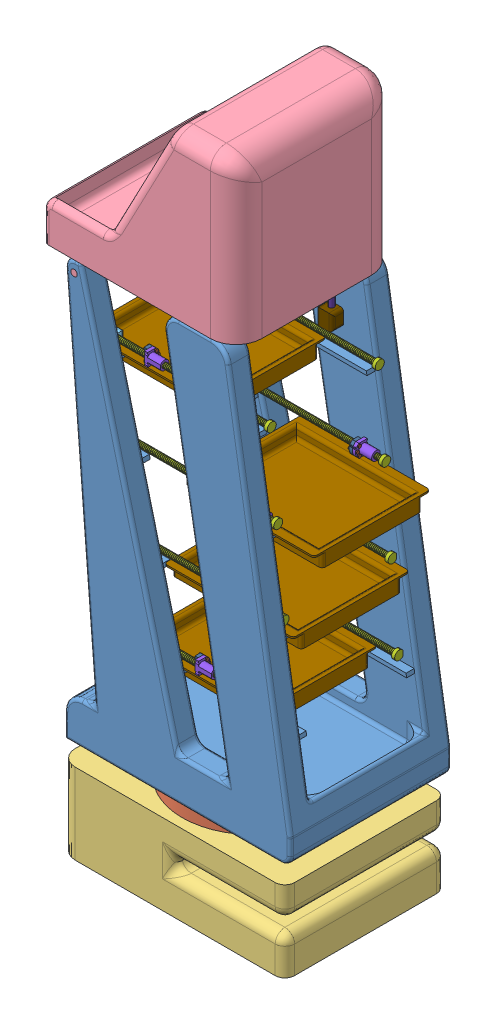
SolidWorks assembly Złożenie1, configuration Domyślna. Lengths in mm.
Overall size (771.86 2135.15 517.31).
75 component instances, 18 part files, 137 mates.
Components (placement in the parent):
- robot_K_1-1: robot_K_1 [Domyślna] at (-167.6884 -51.2285 36.3099) size (700 1300 500)
- robot_K_2-2: robot_K_2 [Domyślna] at (167.3116 -161.2285 286.3099) size (440 200 440)
- robot_K_3-4: robot_K_3 [Domyślna] at (-62.1274 -411.2285 345.4972) x (0 0 -1) z (1 0 0) size (500 250 700)
- robot_K_4-1: robot_K_4 [Domyślna] at (-23.7623 1556.5601 36.3099) size (600 550 517.31)
- motorL-2: motorL [Domyślna] at (-78.6565 231.7434 476.7772) x (0 0 -1) z (0 -1 0) size (37.5 50 47)
- motorL-3: motorL [Domyślna] at (-98.8446 481.7434 476.7772) x (0 0 -1) z (0 -1 0) size (37.5 50 47)
- motorL-4: motorL [Domyślna] at (-118.6565 731.7434 476.7772) x (0 0 -1) z (0 -1 0) size (37.5 50 47)
- motorL-5: motorL [Domyślna] at (-138.6565 981.7434 476.7772) x (0 0 -1) z (0 -1 0) size (37.5 50 47)
- motorR-1: motorR [Domyślna] at (-138.6565 981.7434 116.7772) x (0 0 -1) z (0 -1 0) size (37.5 50 47)
- motorR-2: motorR [Domyślna] at (-118.6565 731.7434 116.7772) x (0 0 -1) z (0 -1 0) size (37.5 50 47)
- motorR-3: motorR [Domyślna] at (-78.6565 231.7434 116.7772) x (0 0 -1) z (0 -1 0) size (37.5 50 47)
- motorR-4: motorR [Domyślna] at (-98.8446 481.7434 116.7772) x (0 0 -1) z (0 -1 0) size (37.5 50 47)
- śruba-1: śruba [Domyślna] at (382.3435 973.7715 118.8099) x (0 0.000202 -1) z (-1 0 0) size (28 28 531.75)
- śruba-2: śruba [Domyślna] at (382.3435 973.7715 453.8099) x (0 0.000188 -1) z (-1 0 0) size (28 28 531.75)
- nakretka-14: nakretka [Default] at (9.7434 973.7715 118.8099) x (1 0 0) z (0 -1 0) size (50 36.5 40)
- nakretka-16: nakretka [Default] at (9.7434 973.7715 453.8099) x (1 0 0) z (0 1 0) size (50 36.5 40)
- tacka-8: tacka [Domyślna] at (-12.1899 908.7715 289.7766) x (0 0 -1) z (1 0 0) size (360 45 400)
- mocowanie_tacka-13: mocowanie_tacka [Default] at (-0.2566 973.7715 118.8099) x (1 0 0) z (0 -1 0) size (10 27.5 40)
- mocowanie_tacka-14: mocowanie_tacka [Default] at (-0.2566 973.7715 453.8099) x (1 0 0) z (0 1 0) size (10 27.5 40)
- sruba_mocowanie-1: sruba_mocowanie [Domyślna] at (-0.2566 960.3365 440.3749) x (0 -0.000382 -1) z (1 0 0) size (10 10 26)
- sruba_mocowanie-3: sruba_mocowanie [Domyślna] at (-0.2566 973.7715 137.8099) x (0 0.000323 -1) z (1 0 0) size (10 10 26)
- sruba_mocowanie-4: sruba_mocowanie [Domyślna] at (-0.2566 960.3365 132.2449) x (0 0.000323 -1) z (1 0 0) size (10 10 26)
- sruba_mocowanie-5: sruba_mocowanie [Domyślna] at (-0.2566 987.2065 132.2449) x (0 0.000323 -1) z (1 0 0) size (10 10 26)
- sruba_mocowanie-6: sruba_mocowanie [Domyślna] at (-0.2566 987.2065 440.3749) x (0 -0.000382 -1) z (1 0 0) size (10 10 26)
- sruba_mocowanie-7: sruba_mocowanie [Domyślna] at (-0.2566 973.7715 434.8099) x (0 -0.000382 -1) z (1 0 0) size (10 10 26)
- sruba_mocowanie-8: sruba_mocowanie [Domyślna] at (321.002 723.7715 434.8099) x (0 -0.000382 -1) z (1 0 0) size (10 10 26)
- sruba_mocowanie-9: sruba_mocowanie [Domyślna] at (321.002 737.2065 440.3749) x (0 -0.000382 -1) z (1 0 0) size (10 10 26)
- sruba_mocowanie-10: sruba_mocowanie [Domyślna] at (321.002 737.2065 132.2449) x (0 0.000323 -1) z (1 0 0) size (10 10 26)
- sruba_mocowanie-11: sruba_mocowanie [Domyślna] at (321.002 710.3365 132.2449) x (0 0.000323 -1) z (1 0 0) size (10 10 26)
- sruba_mocowanie-12: sruba_mocowanie [Domyślna] at (321.002 723.7715 137.8099) x (0 0.000323 -1) z (1 0 0) size (10 10 26)
- sruba_mocowanie-13: sruba_mocowanie [Domyślna] at (321.002 710.3365 440.3749) x (0 -0.000382 -1) z (1 0 0) size (10 10 26)
- mocowanie_tacka-15: mocowanie_tacka [Default] at (321.002 723.7715 453.8099) x (1 0 0) z (0 1 0) size (10 27.5 40)
- mocowanie_tacka-16: mocowanie_tacka [Default] at (321.002 723.7715 118.8099) x (1 0 0) z (0 -1 0) size (10 27.5 40)
- tacka-9: tacka [Domyślna] at (309.0687 658.7715 289.7766) x (0 0 -1) z (1 0 0) size (360 45 400)
- nakretka-17: nakretka [Default] at (331.002 723.7715 453.8099) x (1 0 0) z (0 1 0) size (50 36.5 40)
- nakretka-18: nakretka [Default] at (331.002 723.7715 118.8099) x (1 0 0) z (0 -1 0) size (50 36.5 40)
- śruba-3: śruba [Domyślna] at (402.3435 723.7715 453.8099) x (0 0.000188 -1) z (-1 0 0) size (28 28 531.75)
- śruba-4: śruba [Domyślna] at (402.3435 723.7715 118.8099) x (0 0.000202 -1) z (-1 0 0) size (28 28 531.75)
- sruba_mocowanie-14: sruba_mocowanie [Domyślna] at (256.3597 473.7715 434.8099) x (0 -0.000382 -1) z (1 0 0) size (10 10 26)
- sruba_mocowanie-15: sruba_mocowanie [Domyślna] at (256.3597 487.2065 440.3749) x (0 -0.000382 -1) z (1 0 0) size (10 10 26)
- sruba_mocowanie-16: sruba_mocowanie [Domyślna] at (256.3597 487.2065 132.2449) x (0 0.000323 -1) z (1 0 0) size (10 10 26)
- sruba_mocowanie-17: sruba_mocowanie [Domyślna] at (256.3597 460.3365 132.2449) x (0 0.000323 -1) z (1 0 0) size (10 10 26)
- sruba_mocowanie-18: sruba_mocowanie [Domyślna] at (256.3597 473.7715 137.8099) x (0 0.000323 -1) z (1 0 0) size (10 10 26)
- sruba_mocowanie-19: sruba_mocowanie [Domyślna] at (256.3597 460.3365 440.3749) x (0 -0.000382 -1) z (1 0 0) size (10 10 26)
- mocowanie_tacka-17: mocowanie_tacka [Default] at (256.3597 473.7715 453.8099) x (1 0 0) z (0 1 0) size (10 27.5 40)
- mocowanie_tacka-18: mocowanie_tacka [Default] at (256.3597 473.7715 118.8099) x (1 0 0) z (0 -1 0) size (10 27.5 40)
- tacka-10: tacka [Domyślna] at (244.4263 408.7715 289.7766) x (0 0 -1) z (1 0 0) size (360 45 400)
- nakretka-19: nakretka [Default] at (266.3597 473.7715 453.8099) x (1 0 0) z (0 1 0) size (50 36.5 40)
- nakretka-20: nakretka [Default] at (266.3597 473.7715 118.8099) x (1 0 0) z (0 -1 0) size (50 36.5 40)
- śruba-5: śruba [Domyślna] at (422.1554 473.7715 453.8099) x (0 0.000188 -1) z (-1 0 0) size (28 28 531.75)
- śruba-6: śruba [Domyślna] at (422.1554 473.7715 118.8099) x (0 0.000202 -1) z (-1 0 0) size (28 28 531.75)
- sruba_mocowanie-20: sruba_mocowanie [Domyślna] at (157.5731 223.7715 434.8099) x (0 -0.000382 -1) z (1 0 0) size (10 10 26)
- sruba_mocowanie-21: sruba_mocowanie [Domyślna] at (157.5731 237.2065 440.3749) x (0 -0.000382 -1) z (1 0 0) size (10 10 26)
- sruba_mocowanie-22: sruba_mocowanie [Domyślna] at (157.5731 237.2065 132.2449) x (0 0.000323 -1) z (1 0 0) size (10 10 26)
- sruba_mocowanie-23: sruba_mocowanie [Domyślna] at (157.5731 210.3365 132.2449) x (0 0.000323 -1) z (1 0 0) size (10 10 26)
- sruba_mocowanie-24: sruba_mocowanie [Domyślna] at (157.5731 223.7715 137.8099) x (0 0.000323 -1) z (1 0 0) size (10 10 26)
- sruba_mocowanie-25: sruba_mocowanie [Domyślna] at (157.5731 210.3365 440.3749) x (0 -0.000382 -1) z (1 0 0) size (10 10 26)
- mocowanie_tacka-19: mocowanie_tacka [Default] at (157.5731 223.7715 453.8099) x (1 0 0) z (0 1 0) size (10 27.5 40)
- mocowanie_tacka-20: mocowanie_tacka [Default] at (157.5731 223.7715 118.8099) x (1 0 0) z (0 -1 0) size (10 27.5 40)
- tacka-11: tacka [Domyślna] at (145.6398 158.7715 289.7766) x (0 0 -1) z (1 0 0) size (360 45 400)
- nakretka-21: nakretka [Default] at (167.5731 223.7715 453.8099) x (1 0 0) z (0 1 0) size (50 36.5 40)
- nakretka-22: nakretka [Default] at (167.5731 223.7715 118.8099) x (1 0 0) z (0 -1 0) size (50 36.5 40)
- śruba-7: śruba [Domyślna] at (442.3435 223.7715 453.8099) x (0 0.000188 -1) z (-1 0 0) size (28 28 531.75)
- śruba-8: śruba [Domyślna] at (442.3435 223.7715 118.8099) x (0 0.000202 -1) z (-1 0 0) size (28 28 531.75)
- kolo_D-1: kolo_D [Domyślna] at (320.5228 -376.2285 486.3099) x (0.002489 -0.999997 0) z (0.999997 0.002489 0) size (120 70 120)
- kolo_D-2: kolo_D [Domyślna] at (320.5228 -376.2285 156.3099) x (0.002489 -0.999997 0) z (0.999997 0.002489 0) size (120 70 120)
- do_kola_m-1: do_kola_m [Domyślna] at (-42.0368 -394.1457 263.6106) x (0.819465 0 0.573129) z (-0.573129 0 0.819465) size (40 70 40)
- kolo_M-1: kolo_M [Domyślna] at (-35.8803 -396.2285 274.0179) x (0.819465 0 0.573129) z (-0.573129 0 0.819465) size (50 50 30)
- do_kola_Mm-1: do_kola_Mm [Domyślna] at (-33.0147 -396.2285 269.9206) x (0.819465 0 0.573129) z (0 -1 0) size (16 50 16)
- mocowanie_mechanizmT-1: mocowanie_mechanizmT [Default] at (242.9316 1148.7715 118.8099) x (0 1 0) z (1 0 0) size (50 66.5 40)
- mocowanie_mechanizmT-2: mocowanie_mechanizmT [Default] at (242.9316 1148.7715 453.8099) x (0 1 0) z (-1 0 0) size (50 66.5 40)
- śruba_T-1: śruba_T [Domyślna] at (242.9316 1188.7715 118.8099) x (0.974399 0 -0.224824) z (0 -1 0) size (28 28 190)
- śruba_T-2: śruba_T [Domyślna] at (242.9316 1188.7715 453.8099) x (-0.680666 0 0.732594) z (0 -1 0) size (28 28 190)
- motorT-1: motorT [Domyślna] at (219.9643 1006.7715 432.338) size (50 50 36.09)
- motorT-2: motorT [Domyślna] at (265.899 1006.7715 140.2818) x (-1 0 0) z (0 0 -1) size (50 50 36.09)
Mates (geometry in assembly coordinates):
- Wspólnie2: coincident anti-aligned: circle of robot_K_1-1; circle of robot_K_2-2
- Wspólnie4: coincident anti-aligned: circle of robot_K_2-2; circle of robot_K_3-4
- Wspólnie5: coincident anti-aligned: circle of robot_K_1-1; circle of robot_K_4-1
- Równolegle1: parallel anti-aligned: plane of robot_K_1-1 through (-63.9094 948.7715 441.3099) normal (0 1 0); plane of motorL-5 through (-137.6565 948.7715 466.3099) normal (0 -1 0)
- Wspólnie22: coincident aligned: line of robot_K_1-1 through (-137.6565 948.7715 441.3099) axis (0 0 1); line of motorL-5 through (-137.6565 948.7715 441.3099) axis (0 0 1)
- Wspólnie26: coincident aligned: line of robot_K_1-1 through (-117.6565 698.7715 441.3099) axis (0 0 1); line of motorL-4 through (-117.6565 698.7715 441.3099) axis (0 0 1)
- Wspólnie28: coincident: point of robot_K_1-1; line of motorL-3 through (-97.8446 448.7715 441.3099) axis (0 0 1)
- Wspólnie30: coincident: unknown of robot_K_1-1; line of motorL-2 through (-77.6565 198.7715 441.3099) axis (0 0 1)
- Wspólnie31: coincident anti-aligned: plane of robot_K_1-1 through (-167.6884 38.7715 106.3099) normal (0 0 1); plane of motorR-1 through (-138.6565 981.7434 106.3099) normal (0 0 -1)
- Wspólnie32: coincident aligned: line of robot_K_1-1 through (-137.6565 948.7715 131.3099) axis (0 0 -1); line of motorR-1 through (-137.6565 948.7715 131.3099) axis (0 0 -1)
- Wspólnie33: coincident anti-aligned: plane of robot_K_1-1 through (-167.6884 38.7715 106.3099) normal (0 0 1); plane of motorR-2 through (-118.6565 731.7434 106.3099) normal (0 0 -1)
- Wspólnie34: coincident: unknown of robot_K_1-1; line of motorR-2 through (-117.6565 698.7715 131.3099) axis (0 0 -1)
- Wspólnie36: coincident anti-aligned: plane of robot_K_1-1 through (-167.6884 38.7715 106.3099) normal (0 0 1); plane of motorR-4 through (-98.8446 481.7434 106.3099) normal (0 0 -1)
- Wspólnie37: coincident aligned: line of robot_K_1-1 through (-97.8446 448.7715 131.3099) axis (0 0 -1); line of motorR-4 through (-97.8446 448.7715 131.3099) axis (0 0 -1)
- Wspólnie38: coincident anti-aligned: plane of robot_K_1-1 through (-167.6884 38.7715 106.3099) normal (0 0 1); plane of motorR-3 through (-78.6565 231.7434 106.3099) normal (0 0 -1)
- Wspólnie39: coincident: unknown of robot_K_1-1; line of motorR-3 through (-77.6565 198.7715 131.3099) axis (0 0 -1)
- Koncentryczne3: concentric anti-aligned: circle of motorL-5; circle of śruba-2
- Wspólnie49: coincident aligned: circle of motorR-1; circle of śruba-1
- Wspólnie110: coincident anti-aligned: plane of nakretka-14 through (9.7434 973.7715 134.8099) normal (-1 0 0); plane of mocowanie_tacka-13 through (9.7434 973.7715 137.8099) normal (1 0 0)
- Wspólnie111: coincident aligned: circle of nakretka-14; circle of mocowanie_tacka-13
- Wspólnie112: coincident anti-aligned: plane of nakretka-14 through (9.7434 953.7715 144.8099) normal (0 -1 0); plane of tacka-8 through (-12.1899 953.7715 289.7766) normal (0 1 0)
- Wspólnie113: coincident anti-aligned: plane of nakretka-16 through (9.7434 973.7715 437.8099) normal (-1 0 0); plane of mocowanie_tacka-14 through (9.7434 973.7715 434.8099) normal (1 0 0)
- Wspólnie114: coincident aligned: circle of nakretka-16; circle of mocowanie_tacka-14
- Wspólnie115: coincident anti-aligned: plane of nakretka-16 through (9.7434 953.7715 477.8099) normal (0 -1 0); plane of tacka-8 through (-12.1899 953.7715 289.7766) normal (0 1 0)
- Wspólnie117: coincident anti-aligned: circle of nakretka-16; circle of sruba_mocowanie-6
- Wspólnie120: coincident anti-aligned: circle of nakretka-16; circle of sruba_mocowanie-7
- Wspólnie121: coincident anti-aligned: circle of nakretka-16; circle of sruba_mocowanie-1
- Wspólnie122: coincident anti-aligned: circle of nakretka-14; circle of sruba_mocowanie-5
- Wspólnie123: coincident anti-aligned: circle of nakretka-14; circle of sruba_mocowanie-3
- Wspólnie124: coincident anti-aligned: circle of nakretka-14; circle of sruba_mocowanie-4
- Koncentryczne19: concentric anti-aligned: cylinder of śruba-1 through (-137.6565 973.7715 118.8099) axis (1 0 0) radius 8; cylinder of nakretka-14 through (34.7434 973.7715 118.8099) axis (-1 0 0) radius 8
- Koncentryczne20: concentric anti-aligned: cylinder of śruba-2 through (-137.6565 973.7715 453.8099) axis (1 0 0) radius 8; cylinder of nakretka-16 through (34.7434 973.7715 453.8099) axis (-1 0 0) radius 8
- Wspólnie136: coincident aligned: line of nakretka-14 through (19.7434 953.7715 106.3099) axis (-1 0 0); line of tacka-8 through (204.7434 953.7715 106.3099) axis (-1 0 0)
- Wspólnie137: coincident: unknown of nakretka-14; unknown of tacka-8
- Wspólnie138: coincident: line of nakretka-16 through (19.7434 953.7715 466.3099) axis (-1 0 0); plane of tacka-8 through (-185.2566 953.7715 466.3099) normal (0 0 1)
- Wspólnie139: coincident: unknown of nakretka-16; unknown of tacka-8
- Wspólnie141: coincident anti-aligned: circle of motorL-5; circle of śruba-2
- Wspólnie142: coincident: unknown of tacka-9; unknown of nakretka-18
- Wspólnie143: coincident aligned: line of tacka-9 through (526.002 703.7715 106.3099) axis (-1 0 0); line of nakretka-18 through (341.002 703.7715 106.3099) axis (-1 0 0)
- Wspólnie144: coincident anti-aligned: plane of mocowanie_tacka-15 through (331.002 723.7715 434.8099) normal (1 0 0); plane of nakretka-17 through (331.002 723.7715 437.8099) normal (-1 0 0)
- Wspólnie145: coincident aligned: circle of mocowanie_tacka-16; circle of nakretka-18
- Wspólnie146: coincident anti-aligned: plane of tacka-9 through (309.0687 703.7715 289.7766) normal (0 1 0); plane of nakretka-18 through (331.002 703.7715 144.8099) normal (0 -1 0)
- Wspólnie147: coincident anti-aligned: circle of sruba_mocowanie-9; circle of nakretka-17
- Wspólnie148: coincident anti-aligned: circle of sruba_mocowanie-8; circle of nakretka-17
- Wspólnie149: coincident: plane of tacka-9 through (136.002 703.7715 466.3099) normal (0 0 1); line of nakretka-17 through (341.002 703.7715 466.3099) axis (-1 0 0)
- Wspólnie150: coincident: unknown of tacka-9; unknown of nakretka-17
- Wspólnie151: coincident anti-aligned: plane of mocowanie_tacka-16 through (331.002 723.7715 137.8099) normal (1 0 0); plane of nakretka-18 through (331.002 723.7715 134.8099) normal (-1 0 0)
- Wspólnie152: coincident anti-aligned: circle of sruba_mocowanie-11; circle of nakretka-18
- Wspólnie153: coincident anti-aligned: circle of sruba_mocowanie-12; circle of nakretka-18
- Koncentryczne21: concentric anti-aligned: cylinder of nakretka-18 through (356.002 723.7715 118.8099) axis (-1 0 0) radius 8; cylinder of śruba-4 through (-117.6565 723.7715 118.8099) axis (1 0 0) radius 8
- Koncentryczne22: concentric anti-aligned: cylinder of nakretka-17 through (356.002 723.7715 453.8099) axis (-1 0 0) radius 8; cylinder of śruba-3 through (-117.6565 723.7715 453.8099) axis (1 0 0) radius 8
- Wspólnie154: coincident anti-aligned: circle of sruba_mocowanie-13; circle of nakretka-17
- Wspólnie155: coincident aligned: circle of mocowanie_tacka-15; circle of nakretka-17
- Wspólnie156: coincident anti-aligned: circle of sruba_mocowanie-10; circle of nakretka-18
- Wspólnie157: coincident anti-aligned: plane of tacka-9 through (309.0687 703.7715 289.7766) normal (0 1 0); plane of nakretka-17 through (331.002 703.7715 477.8099) normal (0 -1 0)
- Wspólnie160: coincident anti-aligned: plane of robot_K_1-1 through (404.1453 698.7715 131.3099) normal (0 1 0); plane of tacka-9 through (309.0687 698.7715 289.7766) normal (0 -1 0)
- Wspólnie161: coincident anti-aligned: plane of robot_K_1-1 through (404.1453 698.7715 441.3099) normal (0 1 0); plane of tacka-9 through (309.0687 698.7715 289.7766) normal (0 -1 0)
- Wspólnie162: coincident anti-aligned: plane of robot_K_1-1 through (-167.6884 38.7715 106.3099) normal (0 0 1); plane of tacka-9 through (136.002 703.7715 106.3099) normal (0 0 -1)
- Wspólnie163: coincident anti-aligned: circle of motorL-4; circle of śruba-3
- Wspólnie164: coincident aligned: circle of motorR-2; circle of śruba-4
- Wspólnie165: coincident: unknown of tacka-10; unknown of nakretka-20
- Wspólnie166: coincident aligned: line of tacka-10 through (461.3597 453.7715 106.3099) axis (-1 0 0); line of nakretka-20 through (276.3597 453.7715 106.3099) axis (-1 0 0)
- Wspólnie167: coincident anti-aligned: plane of mocowanie_tacka-17 through (266.3597 473.7715 434.8099) normal (1 0 0); plane of nakretka-19 through (266.3597 473.7715 437.8099) normal (-1 0 0)
- Wspólnie168: coincident aligned: circle of mocowanie_tacka-18; circle of nakretka-20
- Wspólnie169: coincident anti-aligned: plane of tacka-10 through (244.4263 453.7715 289.7766) normal (0 1 0); plane of nakretka-20 through (266.3597 453.7715 144.8099) normal (0 -1 0)
- Wspólnie170: coincident anti-aligned: circle of sruba_mocowanie-15; circle of nakretka-19
- Wspólnie171: coincident anti-aligned: circle of sruba_mocowanie-14; circle of nakretka-19
- Wspólnie172: coincident: plane of tacka-10 through (71.3597 453.7715 466.3099) normal (0 0 1); line of nakretka-19 through (276.3597 453.7715 466.3099) axis (-1 0 0)
- Wspólnie173: coincident: unknown of tacka-10; unknown of nakretka-19
- Wspólnie174: coincident anti-aligned: plane of mocowanie_tacka-18 through (266.3597 473.7715 137.8099) normal (1 0 0); plane of nakretka-20 through (266.3597 473.7715 134.8099) normal (-1 0 0)
- Wspólnie175: coincident anti-aligned: circle of sruba_mocowanie-17; circle of nakretka-20
- Wspólnie176: coincident anti-aligned: circle of sruba_mocowanie-18; circle of nakretka-20
- Koncentryczne23: concentric anti-aligned: cylinder of nakretka-20 through (291.3597 473.7715 118.8099) axis (-1 0 0) radius 8; cylinder of śruba-6 through (-97.8446 473.7715 118.8099) axis (1 0 0) radius 8
- Koncentryczne24: concentric anti-aligned: cylinder of nakretka-19 through (291.3597 473.7715 453.8099) axis (-1 0 0) radius 8; cylinder of śruba-5 through (-97.8446 473.7715 453.8099) axis (1 0 0) radius 8
- Wspólnie177: coincident anti-aligned: circle of sruba_mocowanie-19; circle of nakretka-19
- Wspólnie178: coincident aligned: circle of mocowanie_tacka-17; circle of nakretka-19
- Wspólnie179: coincident anti-aligned: circle of sruba_mocowanie-16; circle of nakretka-20
- Wspólnie180: coincident anti-aligned: plane of tacka-10 through (244.4263 453.7715 289.7766) normal (0 1 0); plane of nakretka-19 through (266.3597 453.7715 477.8099) normal (0 -1 0)
- Wspólnie181: coincident: unknown of tacka-11; unknown of nakretka-22
- Wspólnie182: coincident aligned: line of tacka-11 through (362.5731 203.7715 106.3099) axis (-1 0 0); line of nakretka-22 through (177.5731 203.7715 106.3099) axis (-1 0 0)
- Wspólnie183: coincident anti-aligned: plane of mocowanie_tacka-19 through (167.5731 223.7715 434.8099) normal (1 0 0); plane of nakretka-21 through (167.5731 223.7715 437.8099) normal (-1 0 0)
- Wspólnie184: coincident aligned: circle of mocowanie_tacka-20; circle of nakretka-22
- Wspólnie185: coincident anti-aligned: plane of tacka-11 through (145.6398 203.7715 289.7766) normal (0 1 0); plane of nakretka-22 through (167.5731 203.7715 144.8099) normal (0 -1 0)
- Wspólnie186: coincident anti-aligned: circle of sruba_mocowanie-21; circle of nakretka-21
- Wspólnie187: coincident anti-aligned: circle of sruba_mocowanie-20; circle of nakretka-21
- Wspólnie188: coincident: plane of tacka-11 through (-27.4269 203.7715 466.3099) normal (0 0 1); line of nakretka-21 through (177.5731 203.7715 466.3099) axis (-1 0 0)
- Wspólnie189: coincident: unknown of tacka-11; unknown of nakretka-21
- Wspólnie190: coincident anti-aligned: plane of mocowanie_tacka-20 through (167.5731 223.7715 137.8099) normal (1 0 0); plane of nakretka-22 through (167.5731 223.7715 134.8099) normal (-1 0 0)
- Wspólnie191: coincident anti-aligned: circle of sruba_mocowanie-23; circle of nakretka-22
- Wspólnie192: coincident anti-aligned: circle of sruba_mocowanie-24; circle of nakretka-22
- Koncentryczne25: concentric anti-aligned: cylinder of nakretka-22 through (192.5731 223.7715 118.8099) axis (-1 0 0) radius 8; cylinder of śruba-8 through (-77.6565 223.7715 118.8099) axis (1 0 0) radius 8
- Koncentryczne26: concentric anti-aligned: cylinder of nakretka-21 through (192.5731 223.7715 453.8099) axis (-1 0 0) radius 8; cylinder of śruba-7 through (-77.6565 223.7715 453.8099) axis (1 0 0) radius 8
- Wspólnie193: coincident anti-aligned: circle of sruba_mocowanie-25; circle of nakretka-21
- Wspólnie194: coincident aligned: circle of mocowanie_tacka-19; circle of nakretka-21
- Wspólnie195: coincident anti-aligned: circle of sruba_mocowanie-22; circle of nakretka-22
- Wspólnie196: coincident anti-aligned: plane of tacka-11 through (145.6398 203.7715 289.7766) normal (0 1 0); plane of nakretka-21 through (167.5731 203.7715 477.8099) normal (0 -1 0)
- Wspólnie197: coincident anti-aligned: plane of robot_K_1-1 through (444.941 448.7715 441.3099) normal (0 1 0); plane of tacka-10 through (244.4263 448.7715 289.7766) normal (0 -1 0)
- Wspólnie198: coincident anti-aligned: plane of robot_K_1-1 through (444.941 448.7715 131.3099) normal (0 1 0); plane of tacka-10 through (244.4263 448.7715 289.7766) normal (0 -1 0)
- Wspólnie199: coincident anti-aligned: plane of robot_K_1-1 through (-167.6884 38.7715 466.3099) normal (0 0 -1); plane of tacka-10 through (71.3597 453.7715 466.3099) normal (0 0 1)
- Wspólnie200: coincident anti-aligned: circle of motorL-3; circle of śruba-5
- Wspólnie201: coincident aligned: circle of motorR-4; circle of śruba-6
- Wspólnie202: coincident anti-aligned: plane of robot_K_1-1 through (486.1125 198.7715 441.3099) normal (0 1 0); plane of tacka-11 through (145.6398 198.7715 289.7766) normal (0 -1 0)
- Wspólnie203: coincident anti-aligned: plane of robot_K_1-1 through (486.1125 198.7715 131.3099) normal (0 1 0); plane of tacka-11 through (145.6398 198.7715 289.7766) normal (0 -1 0)
- Wspólnie205: coincident anti-aligned: plane of robot_K_1-1 through (-167.6884 38.7715 466.3099) normal (0 0 -1); plane of tacka-11 through (-27.4269 203.7715 466.3099) normal (0 0 1)
- Wspólnie206: coincident anti-aligned: circle of motorL-2; circle of śruba-7
- Wspólnie207: coincident aligned: circle of motorR-3; circle of śruba-8
- Wspólnie208: coincident aligned: circle of robot_K_3-4; circle of kolo_D-2
- Wspólnie209: coincident aligned: circle of robot_K_3-4; circle of kolo_D-1
- Wspólnie210: coincident anti-aligned: circle of robot_K_3-4; circle of do_kola_m-1
- Wspólnie211: coincident aligned: circle of do_kola_m-1; circle of kolo_M-1
- Wspólnie212: coincident anti-aligned: circle of do_kola_m-1; circle of do_kola_Mm-1
- Równolegle32: parallel aligned: plane of robot_K_3-4 through (-62.1274 -161.2285 345.4972) normal (0 1 0)
- Równolegle33: parallel anti-aligned: plane of robot_K_3-4 through (-184.4772 -161.2285 36.3099) normal (0 0 -1)
- Równolegle35: parallel aligned: plane of nakretka-16 through (9.7434 993.7715 427.8099) normal (0 1 0); plane of mocowanie_tacka-14 through (-0.2566 993.7715 427.8099) normal (0 1 0)
- Równolegle36: parallel aligned: plane of nakretka-14 through (9.7434 993.7715 94.8099) normal (0 1 0); plane of mocowanie_tacka-13 through (-0.2566 993.7715 94.8099) normal (0 1 0)
- Wspólnie221: coincident aligned: plane of mocowanie_tacka-16 through (321.002 743.7715 94.8099) normal (0 1 0); plane of nakretka-18 through (331.002 743.7715 94.8099) normal (0 1 0)
- Wspólnie222: coincident aligned: plane of mocowanie_tacka-18 through (256.3597 493.7715 94.8099) normal (0 1 0); plane of nakretka-20 through (266.3597 493.7715 94.8099) normal (0 1 0)
- Wspólnie223: coincident aligned: plane of mocowanie_tacka-20 through (157.5731 243.7715 94.8099) normal (0 1 0); plane of nakretka-22 through (167.5731 243.7715 94.8099) normal (0 1 0)
- Wspólnie224: coincident aligned: plane of mocowanie_tacka-19 through (157.5731 243.7715 427.8099) normal (0 1 0); plane of nakretka-21 through (167.5731 243.7715 427.8099) normal (0 1 0)
- Wspólnie225: coincident aligned: plane of mocowanie_tacka-17 through (256.3597 493.7715 427.8099) normal (0 1 0); plane of nakretka-19 through (266.3597 493.7715 427.8099) normal (0 1 0)
- Wspólnie226: coincident aligned: plane of mocowanie_tacka-15 through (321.002 743.7715 427.8099) normal (0 1 0); plane of nakretka-17 through (331.002 743.7715 427.8099) normal (0 1 0)
- Wspólnie227: coincident anti-aligned: plane of robot_K_1-1 through (-167.6884 -51.2285 76.3099) normal (0 0 1); plane of mocowanie_mechanizmT-1 through (242.9316 1148.7715 76.3099) normal (0 0 -1)
- Wspólnie228: coincident anti-aligned: plane of robot_K_1-1 through (262.9316 1158.7715 76.3099) normal (0 -1 0); plane of mocowanie_mechanizmT-1 through (242.9316 1158.7715 137.8099) normal (0 1 0)
- Wspólnie229: coincident anti-aligned: plane of robot_K_1-1 through (262.9316 1158.7715 76.3099) normal (-1 0 0); plane of mocowanie_mechanizmT-1 through (262.9316 1148.7715 144.8099) normal (1 0 0)
- Wspólnie230: coincident anti-aligned: plane of robot_K_1-1 through (-167.6884 -51.2285 496.3099) normal (0 0 -1); plane of mocowanie_mechanizmT-2 through (242.9316 1148.7715 496.3099) normal (0 0 1)
- Wspólnie231: coincident anti-aligned: plane of robot_K_1-1 through (262.9316 1158.7715 496.3099) normal (-1 0 0); plane of mocowanie_mechanizmT-2 through (262.9316 1148.7715 477.8099) normal (1 0 0)
- Wspólnie232: coincident anti-aligned: plane of robot_K_1-1 through (262.9316 1148.7715 496.3099) normal (0 1 0); plane of mocowanie_mechanizmT-2 through (242.9316 1148.7715 437.8099) normal (0 -1 0)
- Koncentryczne27: concentric anti-aligned: cylinder of mocowanie_mechanizmT-2 through (242.9316 1173.7715 453.8099) axis (0 -1 0) radius 8; cylinder of śruba_T-2 through (242.9316 1008.7715 453.8099) axis (0 1 0) radius 8
- Koncentryczne33: concentric aligned: cylinder of śruba_T-2 through (242.9316 1008.7715 453.8099) axis (0 1 0) radius 8; cylinder of motorT-1 through (242.9316 1008.7715 453.8099) axis (0 1 0) radius 8
- Prostopadle1: perpendicular: plane of robot_K_1-1 through (-167.6884 38.7715 466.3099) normal (0 0 -1); plane of motorT-1 through (267.9316 1056.7715 430.3099) normal (1 0 0)
- Wspólnie237: coincident anti-aligned: plane of śruba_T-2 through (242.9316 1008.7715 453.8099) normal (0 -1 0); plane of motorT-1 through (242.9316 1008.7715 453.8099) normal (0 1 0)
- Stycznie3: tangent: plane of robot_K_4-1 through (-235.8624 1198.7715 536.3099) normal (0 -1 0); circle of śruba_T-2
- Koncentryczne34: concentric anti-aligned: cylinder of mocowanie_mechanizmT-1 through (242.9316 1173.7715 118.8099) axis (0 -1 0) radius 8; cylinder of śruba_T-1 through (242.9316 1008.7715 118.8099) axis (0 1 0) radius 8
- Stycznie4: tangent: plane of robot_K_4-1 through (-235.8624 1198.7715 536.3099) normal (0 -1 0); circle of śruba_T-1
- Koncentryczne35: concentric aligned: cylinder of śruba_T-1 through (242.9316 1008.7715 118.8099) axis (0 1 0) radius 8; cylinder of motorT-2 through (242.9316 1008.7715 118.8099) axis (0 1 0) radius 8
- Prostopadle2: perpendicular: plane of robot_K_1-1 through (-167.6884 38.7715 106.3099) normal (0 0 1); plane of motorT-2 through (267.9316 1056.7715 142.3099) normal (1 0 0)
- Wspólnie241: coincident anti-aligned: plane of śruba_T-1 through (242.9316 1008.7715 118.8099) normal (0 -1 0); plane of motorT-2 through (242.9316 1008.7715 118.8099) normal (0 1 0)
